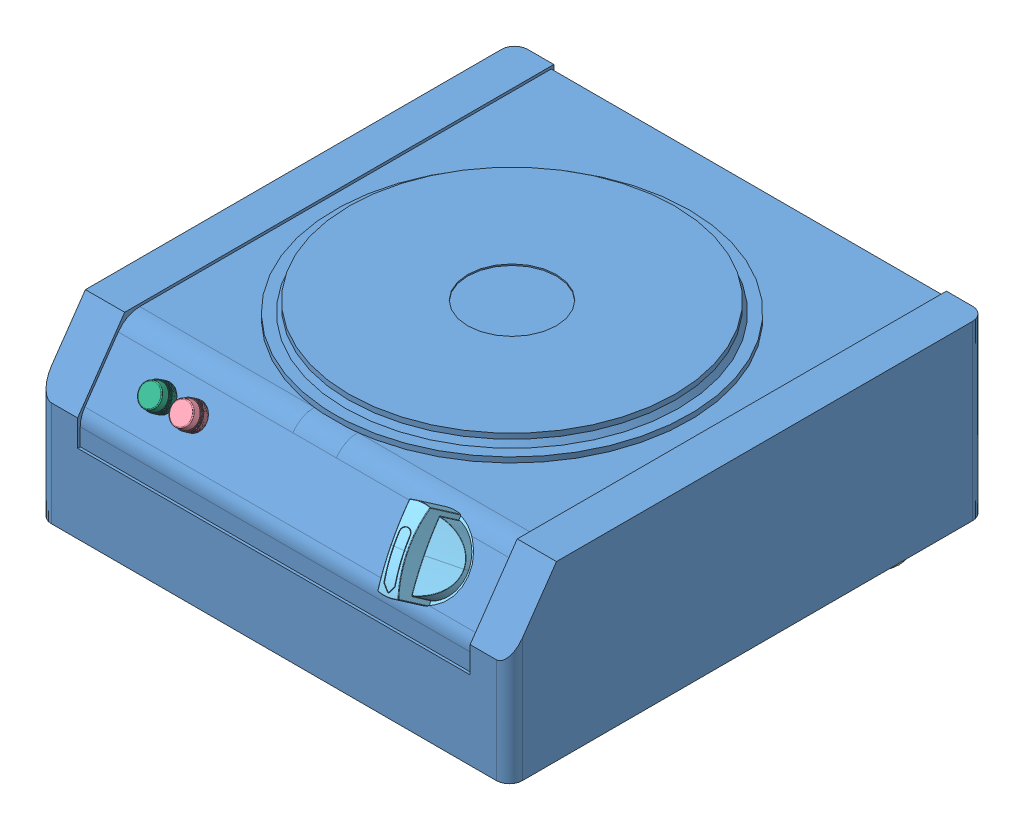
SolidWorks assembly Assem1 fnl, configuration Default. Lengths in mm.
Overall size (180 89.54 206.03).
6 component instances, 6 part files, 10 mates.
Components (placement in the parent):
- Part1-1: Part1 [Default] at (101.4857 116.75 115.3575) size (180 71 182)
- AC_Power_Socket-3_pin_250V_10A_AC-17-2: AC_Power_Socket-3_pin_250V_10A_AC-17 [Default] at (81.3517 114.5291 46.7098) x (-1 0 0) z (0 0 -1) size (66.3 32.3 35.64)
- cover-1: cover [Default] at (-26.0941 68.3791 225.2167) x (0 0 -1) z (1 0 0) size (176.9 14 176.52)
- PanelMountIndicatorLight-2: PanelMountIndicatorLight [Default] at (21.6088 124.6985 222.6423) x (1 0 0) z (0 0.5694 0.822061) size (9.49 9.49 17.46)
- S2SR-S5W2A - Autonics.step-2: S2SR-S5W2A - Autonics.step [Default] at (113.1428 105.5566 195.8068) x (-0.994599 -0.085321 0.059097) z (0 0.5694 0.822061) size (29.98 47.03 75.83)
- PanelMountIndicatorLight1-1: PanelMountIndicatorLight1 [Default] at (9.5649 124.6985 222.6423) x (1 0 0) z (0 0.5694 0.822061) size (9.49 9.49 17.46)
Mates (geometry in assembly coordinates):
- Coincident3: coincident anti-aligned: plane of Part1-1 through (62.1428 115.8791 46.7098) normal (0 0 -1); plane of AC_Power_Socket-3_pin_250V_10A_AC-17-2 through (108.5017 114.5291 46.7098) normal (0 0 1)
- Coincident4: coincident anti-aligned: plane of Part1-1 through (101.4857 98.3791 115.3575) normal (0 1 0); plane of AC_Power_Socket-3_pin_250V_10A_AC-17-2 through (103.3216 98.3791 43.9098) normal (0 -1 0)
- Coincident5: coincident anti-aligned: plane of Part1-1 through (101.4857 71.3791 115.3575) normal (0 -1 0); plane of cover-1 through (-26.0941 71.3791 225.2167) normal (0 1 0)
- Coincident6: coincident anti-aligned: plane of Part1-1 through (-26.0941 71.3791 225.2167) normal (0 0 -1); plane of cover-1 through (-26.0941 71.3791 225.2167) normal (0 0 1)
- Coincident7: coincident anti-aligned: plane of Part1-1 through (-26.0941 131.3791 205.7968) normal (1 0 0); plane of cover-1 through (-26.0941 71.3791 225.2167) normal (-1 0 0)
- Coincident9: coincident anti-aligned: plane of Part1-1 through (-60.8572 108.0855 226.7098) normal (0 0.5694 0.822061); plane of PanelMountIndicatorLight-2 through (21.6088 121.2163 217.6149) normal (0 -0.5694 -0.822061)
- Concentric2: concentric aligned: circle of Part1-1; circle of PanelMountIndicatorLight-2
- Concentric4: concentric anti-aligned: cylinder of Part1-1 through (113.1428 90.094 173.4831) axis (0 0.5694 0.822061) radius 13.5; cylinder of S2SR-S5W2A - Autonics.step-2 through (113.1428 120.3361 217.1444) axis (0 -0.5694 -0.822061) radius 13.7588
- Coincident11: coincident: plane of Part1-1 through (-60.8572 108.0855 226.7098) normal (0 0.5694 0.822061); plane of PanelMountIndicatorLight1-1 through (9.5649 121.2163 217.6149) normal (0 -0.5694 -0.822061)
- Concentric5: concentric anti-aligned: circle of Part1-1; circle of PanelMountIndicatorLight1-1
